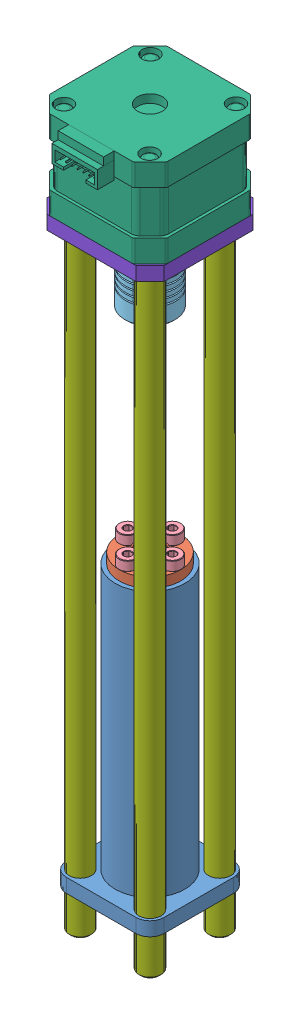
SolidWorks assembly Hydrualic Pressor, configuration Default. Lengths in mm.
Overall size (42 256.7 48).
14 component instances, 8 part files, 24 mates.
Components (placement in the parent):
- CylinderTube-1: CylinderTube [Default] at (47.3326 21.3552 98.033) size (35 100 35)
- tuerca husillo-1: tuerca husillo [Predeterminado] at (47.3326 121.3552 98.033) size (22 31.36 22)
- RodHalf-1: RodHalf [2391N24] at (47.3326 217.0215 98.033) x (0.94051 0 0.339766) z (0 1 0) size (8 8 125.86)
- 91290A381_Black-Oxide Alloy Steel Socket Head Screw-1: 91290A381_Black-Oxide Alloy Steel Socket Head Screw [91290A381] at (39.3326 122.6052 98.033) x (1 0 0) z (0 1 0) size (6.2 6.2 11.7)
- 91290A381_Black-Oxide Alloy Steel Socket Head Screw-2: 91290A381_Black-Oxide Alloy Steel Socket Head Screw [91290A381] at (47.3326 122.6052 106.033) x (1 0 0) z (0 1 0) size (6.2 6.2 11.7)
- 91290A381_Black-Oxide Alloy Steel Socket Head Screw-3: 91290A381_Black-Oxide Alloy Steel Socket Head Screw [91290A381] at (55.3326 122.6052 98.033) x (1 0 0) z (0 1 0) size (6.2 6.2 11.7)
- 91290A381_Black-Oxide Alloy Steel Socket Head Screw-4: 91290A381_Black-Oxide Alloy Steel Socket Head Screw [91290A381] at (47.3326 122.6052 90.033) x (1 0 0) z (0 1 0) size (6.2 6.2 11.7)
- flex coupler v2.step-1: flex coupler v2.step [Default] at (47.3326 201.0215 98.033) x (0.96523 0 -0.261402) z (0.261402 0 0.96523) size (18.93 24 18)
- NM17-1: NM17 [Default] at (47.3326 256.0215 98.033) x (-1 0 0) z (0 1 0) size (42 48 47)
- 1265K66_Rotary Shaft-1: 1265K66_Rotary Shaft [1265K66] at (34.8326 207.3215 110.533) x (0.526531 0 -0.850156) z (0 -1 0) size (8 8 220)
- 1265K66_Rotary Shaft-2: 1265K66_Rotary Shaft [1265K66] at (59.8326 207.3215 85.533) x (0.412855 0 0.910797) z (0 -1 0) size (8 8 220)
- 1265K66_Rotary Shaft-3: 1265K66_Rotary Shaft [1265K66] at (59.8326 207.3215 110.533) x (0.956802 0 -0.290739) z (0 -1 0) size (8 8 220)
- 1265K66_Rotary Shaft-4: 1265K66_Rotary Shaft [1265K66] at (34.8326 207.3215 85.533) x (0.952991 0 -0.302998) z (0 -1 0) size (8 8 220)
- Hydro1-1: Hydro1 [Default] at (26.3326 232.3215 77.033) x (1 0 0) z (0 -1 0) size (42 42 5)
Mates (geometry in assembly coordinates):
- Concentric1: concentric aligned: cylinder of CylinderTube-1 through (47.3326 21.3552 98.033) axis (0 1 0) radius 5; cylinder of tuerca husillo-1 through (47.3326 111.3552 98.033) axis (0 1 0) radius 5
- Concentric2: concentric aligned: cylinder of CylinderTube-1 through (39.3326 21.3552 98.033) axis (0 1 0) radius 1.75; cylinder of tuerca husillo-1 through (39.3326 111.3552 98.033) axis (0 1 0) radius 1.75
- Coincident1: coincident anti-aligned: plane of CylinderTube-1 through (47.3326 121.3552 98.033) normal (0 1 0); plane of tuerca husillo-1 through (47.3326 121.3552 98.033) normal (0 -1 0)
- Concentric3: concentric anti-aligned: cylinder of tuerca husillo-1 through (47.3326 125.8552 98.033) axis (0 -1 0) radius 5; cylinder of RodHalf-1 through (47.3326 342.0215 98.033) axis (0 1 0) radius 4
- Coincident2: coincident anti-aligned: circle of tuerca husillo-1; circle of 91290A381_Black-Oxide Alloy Steel Socket Head Screw-4
- Coincident3: coincident anti-aligned: circle of tuerca husillo-1; circle of 91290A381_Black-Oxide Alloy Steel Socket Head Screw-1
- Coincident4: coincident anti-aligned: circle of tuerca husillo-1; circle of 91290A381_Black-Oxide Alloy Steel Socket Head Screw-3
- Coincident5: coincident anti-aligned: circle of tuerca husillo-1; circle of 91290A381_Black-Oxide Alloy Steel Socket Head Screw-2
- Concentric4: concentric aligned: cylinder of tuerca husillo-1 through (47.3326 125.8552 98.033) axis (0 -1 0) radius 5; cylinder of flex coupler v2.step-1 through (47.3326 236.3352 98.033) axis (0 -1 0) radius 4
- Coincident6: coincident anti-aligned: plane of RodHalf-1 through (43.5705 217.0215 96.6739) normal (0 1 0); plane of flex coupler v2.step-1 through (47.3326 217.0215 98.033) normal (0 -1 0)
- Concentric6: concentric aligned: cylinder of flex coupler v2.step-1 through (47.3326 201.0215 98.033) axis (0 1 0) radius 2.5; cylinder of NM17-1 through (47.3326 217.0215 98.033) axis (0 1 0) radius 2.25
- Parallel1: parallel aligned: plane of CylinderTube-1 through (29.8326 26.3552 115.533) normal (0 0 1); plane of NM17-1 through (32.7468 232.3215 119.033) normal (0 0 1)
- Coincident8: coincident aligned: circle of flex coupler v2.step-1; plane of NM17-1 through (47.3326 217.0215 98.033) normal (0 -1 0)
- Concentric7: concentric anti-aligned: cylinder of CylinderTube-1 through (34.8326 26.3552 110.533) axis (0 -1 0) radius 4; cylinder of 1265K66_Rotary Shaft-1 through (34.8326 7.3215 110.533) axis (0 1 0) radius 4
- Concentric8: concentric anti-aligned: cylinder of CylinderTube-1 through (59.8326 26.3552 85.533) axis (0 -1 0) radius 4; cylinder of 1265K66_Rotary Shaft-2 through (59.8326 7.3215 85.533) axis (0 1 0) radius 4
- Concentric11: concentric anti-aligned: cylinder of CylinderTube-1 through (59.8326 26.3552 110.533) axis (0 -1 0) radius 4; cylinder of 1265K66_Rotary Shaft-3 through (59.8326 7.3215 110.533) axis (0 1 0) radius 4
- Concentric12: concentric anti-aligned: cylinder of CylinderTube-1 through (34.8326 26.3552 85.533) axis (0 -1 0) radius 4; cylinder of 1265K66_Rotary Shaft-4 through (34.8326 7.3215 85.533) axis (0 1 0) radius 4
- Concentric16: concentric anti-aligned: cylinder of NM17-1 through (31.9826 232.3215 82.533) axis (0 1 0) radius 1.5; cylinder of Hydro1-1 through (31.9826 232.3215 82.533) axis (0 -1 0) radius 2
- Concentric17: concentric anti-aligned: cylinder of NM17-1 through (31.9826 232.3215 113.533) axis (0 1 0) radius 1.5; cylinder of Hydro1-1 through (31.9826 232.3215 113.533) axis (0 -1 0) radius 2
- Coincident15: coincident anti-aligned: plane of NM17-1 through (67.3326 232.3215 83.4472) normal (0 -1 0); plane of Hydro1-1 through (26.3326 232.3215 77.033) normal (0 1 0)
- Coincident16: coincident anti-aligned: plane of 1265K66_Rotary Shaft-3 through (57.1684 227.3215 115.5232) normal (0 1 0); plane of Hydro1-1 through (26.3326 227.3215 77.033) normal (0 -1 0)
- Coincident17: coincident anti-aligned: plane of 1265K66_Rotary Shaft-2 through (54.538 227.3215 83.5412) normal (0 1 0); plane of Hydro1-1 through (26.3326 227.3215 77.033) normal (0 -1 0)
- Coincident18: coincident anti-aligned: plane of 1265K66_Rotary Shaft-1 through (36.1271 227.3215 116.0398) normal (0 1 0); plane of Hydro1-1 through (26.3326 227.3215 77.033) normal (0 -1 0)
- Coincident19: coincident anti-aligned: plane of 1265K66_Rotary Shaft-4 through (32.2327 227.3215 90.557) normal (0 1 0); plane of Hydro1-1 through (26.3326 227.3215 77.033) normal (0 -1 0)
